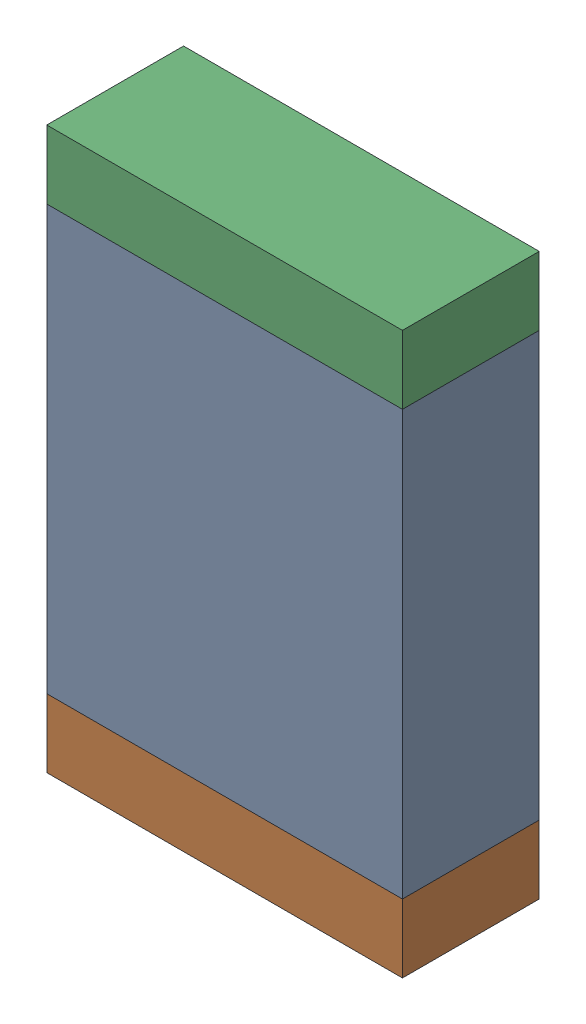
SolidWorks assembly C101, configuration Default. Lengths in mm.
Overall size (1.3 2.05 0.5).
6 component instances, 2 part files, 0 mates.
Components (placement in the parent):
- 836753008-1: 836753008 [Default] at (106.75 71.725 0) size (1.3 1.55 0.5)
  - Extruded_23-1: Extruded_23 [Default] at origin size (1.3 1.55 0.5)
- 836753264-1: 836753264 [Default] at (106.75 70.825 0) size (1.3 0.25 0.5)
  - Extruded_22-1: Extruded_22 [Default] at origin size (1.3 0.25 0.5)
- 836753264-2: 836753264 [Default] at (106.75 72.625 0) size (1.3 0.25 0.5)
  - Extruded_22-1: Extruded_22 [Default] at origin size (1.3 0.25 0.5)
